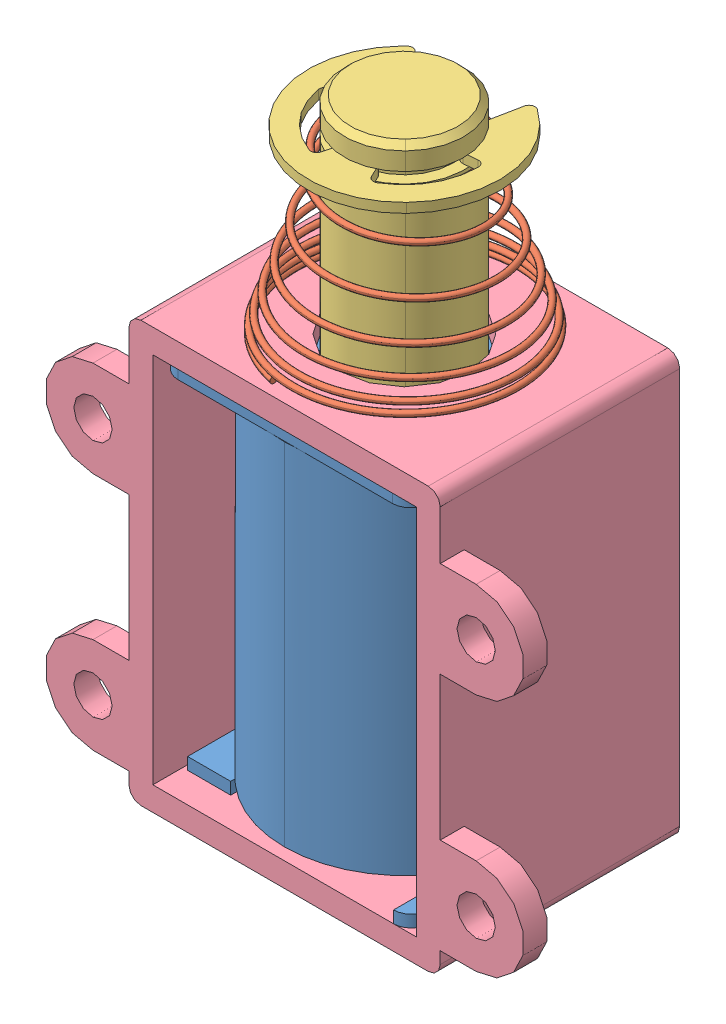
SolidWorks assembly Kicker Assembly, configuration Default. Lengths in mm.
Overall size (40 56.6 22.69).
4 component instances, 4 part files, 5 mates.
Components (placement in the parent):
- Kicker Solenoid Core-1: Kicker Solenoid Core [Default] at (9.5385 32.6382 35.0446) size (21.2 31.5 20)
- Kicker Spring-1: Kicker Spring [Default] at (9.6836 34.5598 25.123) x (0.977237 0.017847 0.2114) z (-0.211435 0.000112 0.977392) size (19 14.33 19.02)
- Kicker Core-1: Kicker Core [Default] at (9.5385 51.5132 25.0446) x (0.718855 0 0.69516) z (0 1 0) size (16 16 56.6)
- kicker Shell-1: kicker Shell [Default] at (-1.4615 32.2382 15.0446) size (40 35.1 20)
Mates (geometry in assembly coordinates):
- Tangent3: tangent: plane of assembly; face of Kicker Spring-1; plane of Kicker Core-1 through (17.0431 48.6132 17.9409) normal (0 -1 0)
- Concentric2: concentric anti-aligned: cylinder of Kicker Solenoid Core-1 through (9.5385 13.4382 25.0446) axis (0 1 0) radius 5.05; cylinder of Kicker Core-1 through (9.5385 48.6132 25.0446) axis (0 -1 0) radius 5
- Lock1: lock: unknown of Kicker Spring-1; unknown of Kicker Core-1
- Concentric5: concentric anti-aligned: cylinder of Kicker Core-1 through (9.5385 48.6132 25.0446) axis (0 -1 0) radius 5; cylinder of kicker Shell-1 through (9.5385 14.2382 25.0446) axis (0 1 0) radius 5.4
- Coincident3: coincident anti-aligned: plane of Kicker Solenoid Core-1 through (19.9885 32.2382 15.0946) normal (0 1 0); plane of kicker Shell-1 through (-1.4615 32.2382 35.0446) normal (0 -1 0)
